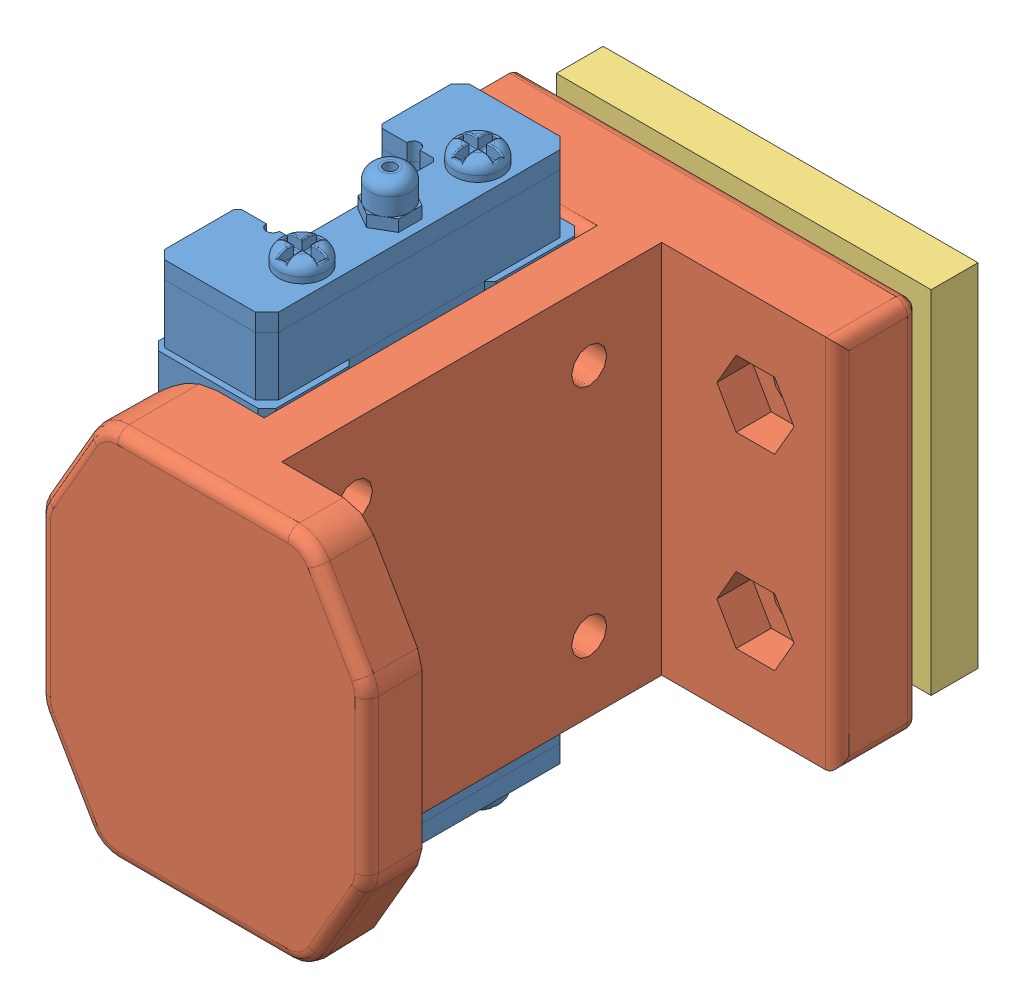
SolidWorks assembly Ползун с зажимом зеркально 3, configuration По умолчанию. Lengths in mm.
Overall size (34 50.47 50.2).
3 component instances, 3 part files, 11 mates.
Components (placement in the parent):
- Ползун-1: Ползун [Default] at (-13 6.5 0) x (0 0 1) z (0 1 0) size (27 10 50.47)
- Тавр обрезаный-2: Тавр обрезаный [По умолчанию] at (0 38.7 -18) x (0 0 1) z (1 0 0) size (44.2 32 34)
- Прижимная планка 3-1: Прижимная планка 3 [По умолчанию] at (-0.7637 -0.7936 -44.6739) x (0 0 1) z (-1 0 0) size (4 30 33)
Mates (geometry in assembly coordinates):
- Совпадение1: coincident anti-aligned: plane of Ползун-1 through (-7 0 6) normal (0 -1 0); plane of assembly through (0 0 0) normal (0 1 0)
- Совпадение2: coincident aligned: plane of Ползун-1 through (0 38.9 -13.5) normal (1 0 0); plane of assembly through (0 0 0) normal (1 0 0)
- Совпадение3: coincident anti-aligned: plane of Ползун-1; plane of assembly through (0 0 0) normal (0 0 1)
- Concentric6: concentric anti-aligned: cylinder of Ползун-1 through (0 12.7 10) axis (1 0 0) radius 1.25; cylinder of Тавр обрезаный-2 through (4 12.7 10) axis (-1 0 0) radius 1.6
- Concentric7: concentric anti-aligned: cylinder of Ползун-1 through (0 32.7 -10) axis (1 0 0) radius 1.25; cylinder of Тавр обрезаный-2 through (4 32.7 -10) axis (-1 0 0) radius 1.6
- Coincident2: coincident anti-aligned: plane of Ползун-1 through (0 38.9 -13.5) normal (1 0 0); plane of Тавр обрезаный-2 through (0 38.7 -18) normal (-1 0 0)
- Concentric8: concentric anti-aligned: cylinder of Тавр обрезаный-2 through (-8 14.7 -23.2) axis (0 0 1) radius 1.6; cylinder of Прижимная планка 3-1 through (-8 14.7 -25.2) axis (0 0 -1) radius 1.6
- Concentric9: concentric anti-aligned: cylinder of Тавр обрезаный-2 through (12 30.7 -23.2) axis (0 0 1) radius 1.6; cylinder of Прижимная планка 3-1 through (12 30.7 -25.2) axis (0 0 -1) radius 1.6
- Concentric10: concentric anti-aligned: cylinder of Тавр обрезаный-2 through (-8 30.7 -23.2) axis (0 0 1) radius 1.6; cylinder of Прижимная планка 3-1 through (-8 30.7 -25.2) axis (0 0 -1) radius 1.6
- Concentric11: concentric aligned: circle of Тавр обрезаный-2; circle of Прижимная планка 3-1
- Coincident5: coincident anti-aligned: plane of Прижимная планка 3-1 through (-0.7637 -0.7936 -25.2) normal (0 0 1); plane of assembly through (0 0 -25.2) normal (0 0 -1)
